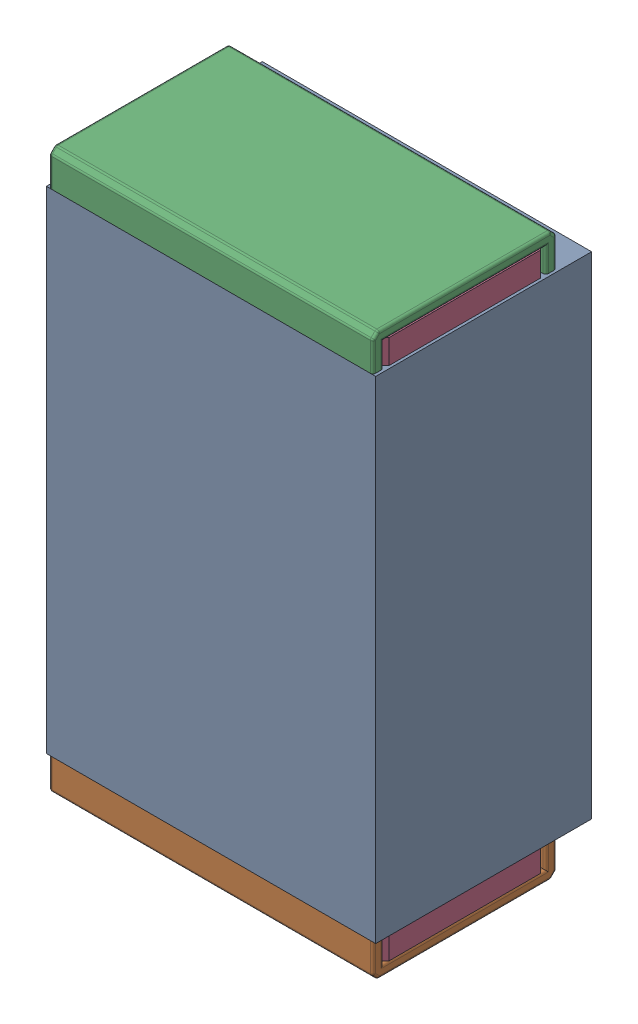
SolidWorks assembly R21, configuration Default. Lengths in mm.
Overall size (0.61 1.04 0.4).
3 component instances, 2 part files, 0 mates.
Components (placement in the parent):
- 1088881848-1: 1088881848 [Default] at (9 31.775 -2.044) size (0.61 0.91 0.4)
  - Extruded-1-1: Extruded-1 [Default] at origin size (0.61 0.91 0.4)
- R0402-1: R0402 [Default] at (9 31.7749 -1.644) x (0 -1 0) z (1 0 0) size (1.04 0.34 0.6)
